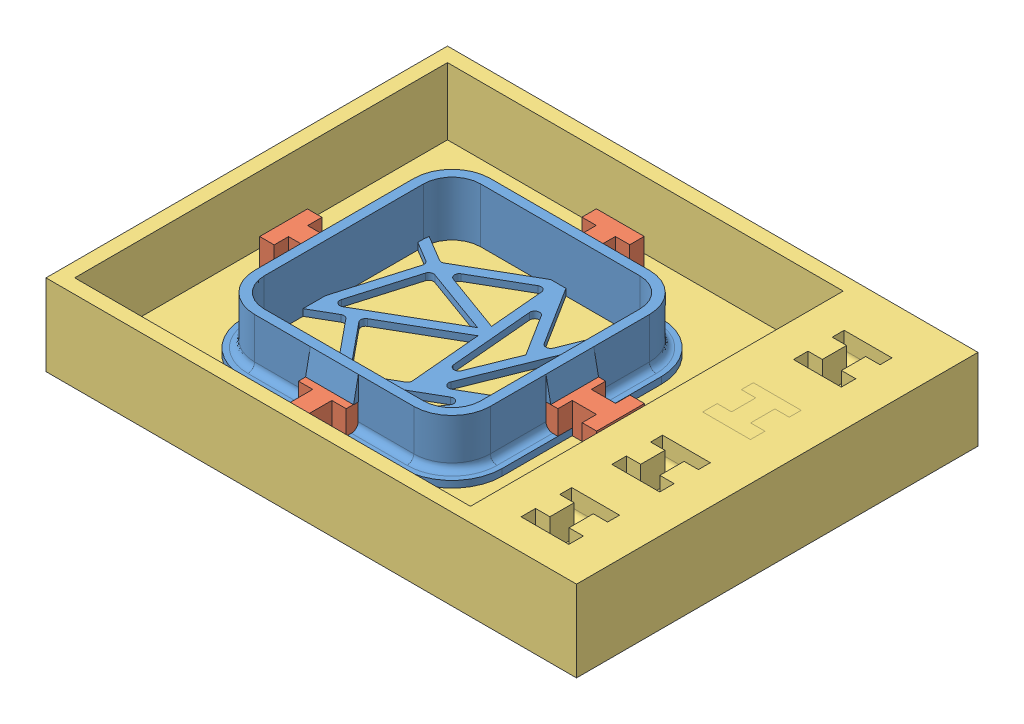
SolidWorks assembly assembly final2, configuration Default. Lengths in mm.
Overall size (111 17 84).
6 component instances, 3 part files, 8 mates.
Components (placement in the parent):
- 2.2-1: 2.2 [Default] at (-51.596 10.5861 -9.7368) size (54.3 11.4 54.3)
- blocks_silicon-1: blocks_silicon [Default] at (-37.2385 5.0946 16.9074) size (10 6.4 10.6)
- blocks_silicon-2: blocks_silicon [Default] at (-24.9518 5.0946 -24.0944) x (0 0 -1) z (1 0 0) size (10 6.4 10.6)
- blocks_silicon-3: blocks_silicon [Default] at (-66.0036 5.0946 -36.3811) x (-1 0 0) z (0 0 -1) size (10 6.4 10.6)
- blocks_silicon-4: blocks_silicon [Default] at (-78.2402 5.0946 4.6207) x (0 0 1) z (-1 0 0) size (10 6.4 10.6)
- vasca2-1: vasca2 [Default] at (-38.6134 9.1861 -9.2961) size (111 17 84)
Mates (geometry in assembly coordinates):
- Coincident9: coincident aligned: plane of 2.2-1 through (-34.946 20.5861 -32.3868) normal (0 0 1); plane of ? through (-32.4563 6.9551 -32.3868) normal (0 0 1)
- Coincident10: coincident: point of 2.2-1; point of blocks_silicon-4
- Coincident11: coincident: point of 2.2-1; point of blocks_silicon-3
- Coincident12: coincident: point of 2.2-1; point of blocks_silicon-1
- Coincident13: coincident: point of 2.2-1; point of blocks_silicon-2
- Coincident14: coincident anti-aligned: plane of 2.2-1 through (-34.946 9.1861 -26.3868) normal (0 -1 0); plane of ? through (-51.7145 9.1861 -9.6661) normal (0 1 0)
- Perpendicular1: perpendicular: line of 2.2-1 through (-74.246 20.5861 -26.3868) axis (0 0 1); line of ? through (8.3896 9.1861 -9.6661) axis (-1 0 0)
- Coincident15: coincident anti-aligned: plane of 2.2-1 through (-34.946 9.1861 -26.3868) normal (0 -1 0); plane of vasca2-1 through (-38.6134 9.1861 -9.2961) normal (0 1 0)
